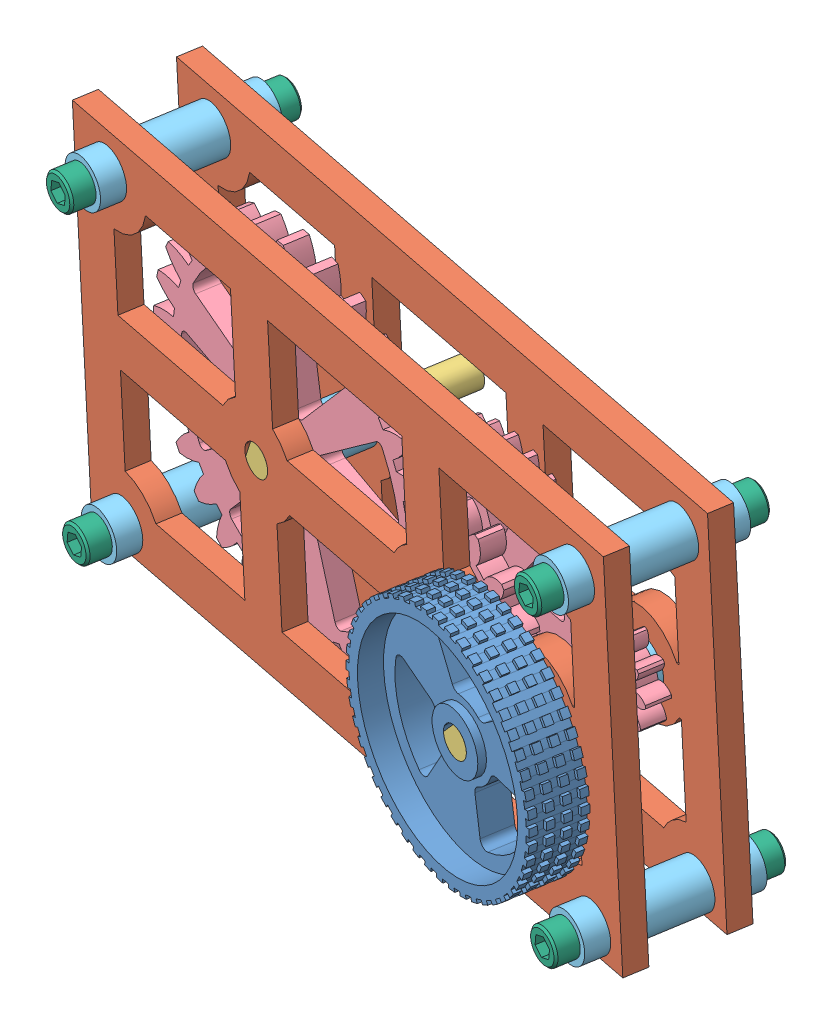
SolidWorks assembly gearbox, configuration Default. Lengths in mm.
Overall size (100.67 63.61 57.73).
40 component instances, 6 part files, 55 mates.
Components (placement in the parent):
- knob-1: knob [Default] at (7.9553 -111.4931 123.7361) x (-0.201949 -0.036611 0.978712) z (0.719883 -0.683113 0.122989) size (7 31.98 32.04)
- plate-1: plate [Default] at (-21.9045 -111.291 100.2126) x (-0.979202 -0.012363 -0.202512) z (0.201949 0.036611 -0.978712) size (93 50 3)
- sub 1-1: sub 1 [Default] at (23.1272 -130.4427 130.6283) x (-0.664068 -0.729395 -0.164309) z (0.201949 0.036611 -0.978712) size (13.97 13.6 25)
  - axle-1: axle [25 mm Tall] at (-2.6141 24.7144 -0.6247) size (4 3.5 25)
  - root_gear-1: root_gear [10T 1.0Mod] at (-2.6141 24.7144 17.3753) x (0.981831 0.18976 0) z (0 0 1) size (12 11.53 3)
  - spacer-3: spacer [1 mm Tall] at (-2.6141 24.7144 20.3753) size (6.2 6.2 1)
  - spacer-4: spacer [5 mm Tall] at (-2.6141 24.7144 12.3753) size (6.2 6.2 5)
- sub 2-1: sub 2 [Default] at (-36.8905 -107.9865 121.4817) x (0.835581 0.514845 0.191674) z (0.201949 0.036611 -0.978712) size (32 31.89 15)
  - root_gear-1: root_gear [30T 1.0Mod] at (18.8313 15.9897 19.7218) size (32 31.89 3)
  - root_gear-2: root_gear [10T 1.5Mod] at (18.8313 15.9897 15.7218) x (0.373168 0.927764 0) z (0 0 1) size (18 17.3 3)
  - axle-1: axle [15 mm Tall] at (18.8313 15.9897 11.7218) x (-0.639963 0.768406 0) z (0 0 1) size (4 3.5 15)
  - spacer-1: spacer [1 mm Tall] at (18.8313 15.9897 14.7218) size (6.2 6.2 1)
  - spacer-2: spacer [1 mm Tall] at (18.8313 15.9897 22.7218) size (6.2 6.2 1)
  - spacer-3: spacer [1 mm Tall] at (18.8313 15.9897 18.7218) size (6.2 6.2 1)
- sub 3-1: sub 3 [Default] at (-13.7078 -137.0358 71.116) x (0.370962 0.921986 0.111033) z (-0.201949 -0.036611 0.978712) size (48 47.84 25)
  - root_gear-1: root_gear [30T 1.5Mod] at (17.5723 27.0157 34.1899) size (48 47.84 3)
  - axle-1: axle [25 mm Tall] at (17.5723 27.0157 16.1899) size (4 3.5 25)
  - spacer-1: spacer [5 mm Tall] at (17.5723 27.0157 29.1899) size (6.2 6.2 5)
  - spacer-2: spacer [1 mm Tall] at (17.5723 27.0157 37.1899) size (6.2 6.2 1)
- plate-2: plate [Default] at (-24.3278 -111.7304 111.9571) x (-0.979202 -0.012363 -0.202512) z (0.201949 0.036611 -0.978712) size (93 50 3)
- spacer-10: spacer [2.85 mm ID] at (18.3421 -90.7929 109.2839) x (0.9729 0.107405 0.204767) z (-0.201949 -0.036611 0.978712) size (6.2 6.2 9)
- spacer-11: spacer [2.85 mm ID] at (-61.0956 -133.5261 91.2941) x (0.9729 0.107405 0.204767) z (-0.201949 -0.036611 0.978712) size (6.2 6.2 9)
- spacer-12: spacer [2.85 mm ID] at (-61.9104 -91.8061 92.6866) x (0.9729 0.107405 0.204767) z (-0.201949 -0.036611 0.978712) size (6.2 6.2 9)
- spacer-13: spacer [2.85 mm ID] at (19.1569 -132.5128 107.8914) x (0.9729 0.107405 0.204767) z (-0.201949 -0.036611 0.978712) size (6.2 6.2 9)
- spacer-14: spacer [3 mm ID] at (-64.3338 -92.2455 104.4311) x (0.979391 -0.010837 0.201684) z (-0.201949 -0.036611 0.978712) size (6.2 6.2 3)
- spacer-15: spacer [3 mm ID] at (19.5538 -90.5732 103.4116) x (0.979391 -0.010837 0.201684) z (-0.201949 -0.036611 0.978712) size (6.2 6.2 3)
- spacer-16: spacer [3 mm ID] at (20.3686 -132.2932 102.0191) x (0.979391 -0.010837 0.201684) z (-0.201949 -0.036611 0.978712) size (6.2 6.2 3)
- spacer-17: spacer [3 mm ID] at (-59.884 -133.3064 85.4218) x (0.979391 -0.010837 0.201684) z (-0.201949 -0.036611 0.978712) size (6.2 6.2 3)
- spacer-18: spacer [3 mm ID] at (-60.6987 -91.5865 86.8143) x (0.979391 -0.010837 0.201684) z (-0.201949 -0.036611 0.978712) size (6.2 6.2 3)
- spacer-19: spacer [3 mm ID] at (15.9187 -91.2322 121.0284) x (0.979391 -0.010837 0.201684) z (-0.201949 -0.036611 0.978712) size (6.2 6.2 3)
- spacer-20: spacer [3 mm ID] at (16.7335 -132.9522 119.6359) x (0.979391 -0.010837 0.201684) z (-0.201949 -0.036611 0.978712) size (6.2 6.2 3)
- spacer-21: spacer [3 mm ID] at (-63.519 -133.9654 103.0386) x (0.979391 -0.010837 0.201684) z (-0.201949 -0.036611 0.978712) size (6.2 6.2 3)
- socket head cap screw_ai-4: socket head cap screw_ai [HX-SHCS 0.112-40x0.375x0.375-N] at (14.7384 -91.4462 126.7488) x (0.201949 0.036611 -0.978712) z (0.968271 -0.157654 0.193897) size (12.37 4.65 4.65)
- socket head cap screw_ai-5: socket head cap screw_ai [HX-SHCS 0.112-40x0.375x0.375-N] at (20.1283 -90.4691 100.6274) x (-0.201949 -0.036611 0.978712) z (-0.95645 -0.20767 -0.205124) size (12.37 4.65 4.65)
- socket head cap screw_ai-6: socket head cap screw_ai [HX-SHCS 0.112-40x0.375x0.375-N] at (-60.1242 -91.4823 84.03) x (-0.201949 -0.036611 0.978712) z (-0.95645 -0.20767 -0.205124) size (12.37 4.65 4.65)
- socket head cap screw_ai-7: socket head cap screw_ai [HX-SHCS 0.112-40x0.375x0.375-N] at (-59.3095 -133.2023 82.6375) x (-0.201949 -0.036611 0.978712) z (-0.95645 -0.20767 -0.205124) size (12.37 4.65 4.65)
- socket head cap screw_ai-8: socket head cap screw_ai [HX-SHCS 0.112-40x0.375x0.375-N] at (20.9431 -132.189 99.2349) x (-0.201949 -0.036611 0.978712) z (-0.95645 -0.20767 -0.205124) size (12.37 4.65 4.65)
- socket head cap screw_ai-9: socket head cap screw_ai [HX-SHCS 0.112-40x0.375x0.375-N] at (-65.5141 -92.4595 110.1515) x (0.201949 0.036611 -0.978712) z (0.968271 -0.157654 0.193897) size (12.37 4.65 4.65)
- socket head cap screw_ai-10: socket head cap screw_ai [HX-SHCS 0.112-40x0.375x0.375-N] at (-64.6994 -134.1794 108.759) x (0.201949 0.036611 -0.978712) z (0.968271 -0.157654 0.193897) size (12.37 4.65 4.65)
- socket head cap screw_ai-11: socket head cap screw_ai [HX-SHCS 0.112-40x0.375x0.375-N] at (15.5531 -133.1661 125.3563) x (0.201949 0.036611 -0.978712) z (0.968271 -0.157654 0.193897) size (12.37 4.65 4.65)
Mates (geometry in assembly coordinates):
- Concentric10: concentric aligned: cylinder of plate-1 through (11.9942 -110.7608 104.1618) axis (-0.201949 -0.036611 0.978712) radius 2; cylinder of sub 1-1/axle-1 through (11.9942 -110.7608 104.1618) axis (-0.201949 -0.036611 0.978712) radius 2
- Concentric11: concentric aligned: cylinder of plate-1 through (-7.5898 -111.0081 100.1116) axis (-0.201949 -0.036611 0.978712) radius 2; cylinder of sub 2-1/axle-1 through (-7.5898 -111.0081 100.1116) axis (-0.201949 -0.036611 0.978712) radius 2
- Concentric12: concentric anti-aligned: cylinder of plate-1 through (-36.9658 -111.379 94.0362) axis (-0.201949 -0.036611 0.978712) radius 2; cylinder of sub 3-1/axle-1 through (-39.9951 -111.9282 108.7169) axis (0.201949 0.036611 -0.978712) radius 2
- Coincident3: coincident anti-aligned: plane of plate-1 through (-21.9045 -111.291 100.2126) normal (-0.201949 -0.036611 0.978712); plane of sub 3-1/spacer-1 through (-37.5717 -111.4888 96.9724) normal (0.201949 0.036611 -0.978712)
- Coincident4: coincident anti-aligned: plane of plate-1 through (-21.9045 -111.291 100.2126) normal (-0.201949 -0.036611 0.978712); plane of sub 2-1/spacer-2 through (-8.1956 -111.1179 103.0477) normal (0.201949 0.036611 -0.978712)
- Coincident5: coincident anti-aligned: plane of plate-1 through (-21.9045 -111.291 100.2126) normal (-0.201949 -0.036611 0.978712); plane of sub 1-1/spacer-3 through (11.3884 -110.8707 107.098) normal (0.201949 0.036611 -0.978712)
- Concentric24: concentric anti-aligned: cylinder of knob-1 through (7.9553 -111.4931 123.7361) axis (0.201949 0.036611 -0.978712) radius 2; cylinder of sub 1-1/axle-1 through (11.9942 -110.7608 104.1618) axis (-0.201949 -0.036611 0.978712) radius 2
- Coincident18: coincident aligned: plane of knob-1 through (4.066 -108.9437 128.1377) normal (-0.201949 -0.036611 0.978712); plane of sub 1-1/axle-1 through (6.9455 -111.6761 128.6296) normal (-0.201949 -0.036611 0.978712)
- Concentric34: concentric anti-aligned: cylinder of plate-2 through (16.5246 -91.1224 118.0923) axis (-0.201949 -0.036611 0.978712) radius 1.5; cylinder of spacer-10 through (16.5246 -91.1224 118.0923) axis (0.201949 0.036611 -0.978712) radius 1.425
- Coincident27: coincident anti-aligned: plane of plate-2 through (-23.722 -111.6205 109.021) normal (0.201949 0.036611 -0.978712); plane of spacer-10 through (16.5246 -91.1224 118.0923) normal (-0.201949 -0.036611 0.978712)
- Coincident28: coincident anti-aligned: plane of plate-1 through (-21.9045 -111.291 100.2126) normal (-0.201949 -0.036611 0.978712); plane of spacer-10 through (18.3421 -90.7929 109.2839) normal (0.201949 0.036611 -0.978712)
- Concentric35: concentric anti-aligned: cylinder of plate-1 through (18.948 -90.6831 106.3477) axis (-0.201949 -0.036611 0.978712) radius 1.5; cylinder of spacer-10 through (16.5246 -91.1224 118.0923) axis (0.201949 0.036611 -0.978712) radius 1.425
- Coincident29: coincident anti-aligned: plane of plate-1 through (-21.9045 -111.291 100.2126) normal (-0.201949 -0.036611 0.978712); plane of spacer-11 through (-61.0956 -133.5261 91.2941) normal (0.201949 0.036611 -0.978712)
- Coincident30: coincident anti-aligned: plane of plate-2 through (-23.722 -111.6205 109.021) normal (0.201949 0.036611 -0.978712); plane of spacer-11 through (-62.9132 -133.8556 100.1025) normal (-0.201949 -0.036611 0.978712)
- Concentric36: concentric anti-aligned: cylinder of plate-1 through (-60.4898 -133.4162 88.3579) axis (-0.201949 -0.036611 0.978712) radius 1.5; cylinder of spacer-11 through (-62.9132 -133.8556 100.1025) axis (0.201949 0.036611 -0.978712) radius 1.425
- Concentric37: concentric anti-aligned: cylinder of plate-2 through (-62.9132 -133.8556 100.1025) axis (-0.201949 -0.036611 0.978712) radius 1.5; cylinder of spacer-11 through (-62.9132 -133.8556 100.1025) axis (0.201949 0.036611 -0.978712) radius 1.425
- Concentric38: concentric anti-aligned: cylinder of plate-1 through (-61.3045 -91.6963 89.7504) axis (-0.201949 -0.036611 0.978712) radius 1.5; cylinder of spacer-12 through (-63.7279 -92.1356 101.495) axis (0.201949 0.036611 -0.978712) radius 1.425
- Concentric39: concentric anti-aligned: cylinder of plate-1 through (19.7627 -132.403 104.9552) axis (-0.201949 -0.036611 0.978712) radius 1.5; cylinder of spacer-13 through (17.3393 -132.8423 116.6998) axis (0.201949 0.036611 -0.978712) radius 1.425
- Coincident31: coincident anti-aligned: plane of plate-1 through (-21.9045 -111.291 100.2126) normal (-0.201949 -0.036611 0.978712); plane of spacer-12 through (-61.9104 -91.8061 92.6866) normal (0.201949 0.036611 -0.978712)
- Coincident32: coincident anti-aligned: plane of plate-1 through (-21.9045 -111.291 100.2126) normal (-0.201949 -0.036611 0.978712); plane of spacer-13 through (19.1569 -132.5128 107.8914) normal (0.201949 0.036611 -0.978712)
- Coincident33: coincident anti-aligned: plane of plate-1 through (-21.2986 -111.1812 97.2764) normal (0.201949 0.036611 -0.978712); plane of spacer-15 through (18.948 -90.6831 106.3477) normal (-0.201949 -0.036611 0.978712)
- Coincident34: coincident anti-aligned: plane of plate-1 through (-21.2986 -111.1812 97.2764) normal (0.201949 0.036611 -0.978712); plane of spacer-18 through (-61.3045 -91.6963 89.7504) normal (-0.201949 -0.036611 0.978712)
- Coincident35: coincident anti-aligned: plane of plate-1 through (-21.2986 -111.1812 97.2764) normal (0.201949 0.036611 -0.978712); plane of spacer-17 through (-60.4898 -133.4162 88.3579) normal (-0.201949 -0.036611 0.978712)
- Coincident36: coincident anti-aligned: plane of plate-1 through (-21.2986 -111.1812 97.2764) normal (0.201949 0.036611 -0.978712); plane of spacer-16 through (19.7627 -132.403 104.9552) normal (-0.201949 -0.036611 0.978712)
- Coincident37: coincident anti-aligned: plane of plate-2 through (-24.3278 -111.7304 111.9571) normal (-0.201949 -0.036611 0.978712); plane of spacer-20 through (16.7335 -132.9522 119.6359) normal (0.201949 0.036611 -0.978712)
- Coincident38: coincident anti-aligned: plane of plate-2 through (-24.3278 -111.7304 111.9571) normal (-0.201949 -0.036611 0.978712); plane of spacer-19 through (15.9187 -91.2322 121.0284) normal (0.201949 0.036611 -0.978712)
- Coincident39: coincident anti-aligned: plane of plate-2 through (-24.3278 -111.7304 111.9571) normal (-0.201949 -0.036611 0.978712); plane of spacer-21 through (-63.519 -133.9654 103.0386) normal (0.201949 0.036611 -0.978712)
- Coincident40: coincident anti-aligned: plane of plate-2 through (-24.3278 -111.7304 111.9571) normal (-0.201949 -0.036611 0.978712); plane of spacer-14 through (-64.3338 -92.2455 104.4311) normal (0.201949 0.036611 -0.978712)
- Concentric40: concentric anti-aligned: cylinder of plate-2 through (16.5246 -91.1224 118.0923) axis (-0.201949 -0.036611 0.978712) radius 1.5; cylinder of spacer-19 through (15.3129 -91.342 123.9645) axis (0.201949 0.036611 -0.978712) radius 1.5
- Concentric41: concentric anti-aligned: cylinder of plate-2 through (-63.7279 -92.1356 101.495) axis (-0.201949 -0.036611 0.978712) radius 1.5; cylinder of spacer-14 through (-64.9396 -92.3553 107.3672) axis (0.201949 0.036611 -0.978712) radius 1.5
- Concentric42: concentric anti-aligned: cylinder of plate-2 through (-62.9132 -133.8556 100.1025) axis (-0.201949 -0.036611 0.978712) radius 1.5; cylinder of spacer-21 through (-64.1249 -134.0752 105.9747) axis (0.201949 0.036611 -0.978712) radius 1.5
- Concentric43: concentric anti-aligned: cylinder of plate-2 through (17.3393 -132.8423 116.6998) axis (-0.201949 -0.036611 0.978712) radius 1.5; cylinder of spacer-20 through (16.1276 -133.062 122.572) axis (0.201949 0.036611 -0.978712) radius 1.5
- Concentric44: concentric anti-aligned: cylinder of plate-1 through (19.7627 -132.403 104.9552) axis (-0.201949 -0.036611 0.978712) radius 1.5; cylinder of spacer-16 through (19.7627 -132.403 104.9552) axis (0.201949 0.036611 -0.978712) radius 1.5
- Concentric45: concentric anti-aligned: cylinder of plate-1 through (18.948 -90.6831 106.3477) axis (-0.201949 -0.036611 0.978712) radius 1.5; cylinder of spacer-15 through (18.948 -90.6831 106.3477) axis (0.201949 0.036611 -0.978712) radius 1.5
- Concentric47: concentric anti-aligned: cylinder of plate-1 through (-61.3045 -91.6963 89.7504) axis (-0.201949 -0.036611 0.978712) radius 1.5; cylinder of spacer-18 through (-61.3045 -91.6963 89.7504) axis (0.201949 0.036611 -0.978712) radius 1.5
- Concentric48: concentric anti-aligned: cylinder of plate-1 through (-60.4898 -133.4162 88.3579) axis (-0.201949 -0.036611 0.978712) radius 1.5; cylinder of spacer-17 through (-60.4898 -133.4162 88.3579) axis (0.201949 0.036611 -0.978712) radius 1.5
- Concentric49: concentric anti-aligned: cylinder of spacer-19 through (15.3129 -91.342 123.9645) axis (0.201949 0.036611 -0.978712) radius 1.5; cylinder of socket head cap screw_ai-4 through (8.3265 -92.6086 157.8229) axis (-0.201949 -0.036611 0.978712) radius 2.3241
- Coincident41: coincident anti-aligned: plane of spacer-19 through (15.3129 -91.342 123.9645) normal (-0.201949 -0.036611 0.978712); plane of socket head cap screw_ai-4 through (15.655 -89.0486 124.1209) normal (0.201949 0.036611 -0.978712)
- Concentric50: concentric aligned: cylinder of spacer-15 through (18.948 -90.6831 106.3477) axis (0.201949 0.036611 -0.978712) radius 1.5; cylinder of socket head cap screw_ai-5 through (26.5402 -89.3067 69.5533) axis (0.201949 0.036611 -0.978712) radius 2.3241
- Coincident42: coincident anti-aligned: plane of spacer-15 through (19.5538 -90.5732 103.4116) normal (0.201949 0.036611 -0.978712); plane of socket head cap screw_ai-5 through (19.064 -88.3014 103.3955) normal (-0.201949 -0.036611 0.978712)
- Concentric51: concentric aligned: cylinder of spacer-18 through (-61.3045 -91.6963 89.7504) axis (0.201949 0.036611 -0.978712) radius 1.5; cylinder of socket head cap screw_ai-6 through (-53.7123 -90.3199 52.9559) axis (0.201949 0.036611 -0.978712) radius 2.3241
- Coincident43: coincident anti-aligned: plane of spacer-18 through (-60.6987 -91.5865 86.8143) normal (0.201949 0.036611 -0.978712); plane of socket head cap screw_ai-6 through (-61.1885 -89.3146 86.7982) normal (-0.201949 -0.036611 0.978712)
- Concentric52: concentric aligned: cylinder of spacer-17 through (-60.4898 -133.4162 88.3579) axis (0.201949 0.036611 -0.978712) radius 1.5; cylinder of socket head cap screw_ai-7 through (-52.8976 -132.0399 51.5635) axis (0.201949 0.036611 -0.978712) radius 2.3241
- Coincident44: coincident anti-aligned: plane of spacer-17 through (-59.884 -133.3064 85.4218) normal (0.201949 0.036611 -0.978712); plane of socket head cap screw_ai-7 through (-60.3738 -131.0346 85.4057) normal (-0.201949 -0.036611 0.978712)
- Concentric53: concentric aligned: cylinder of spacer-16 through (19.7627 -132.403 104.9552) axis (0.201949 0.036611 -0.978712) radius 1.5; cylinder of socket head cap screw_ai-8 through (27.3549 -131.0266 68.1608) axis (0.201949 0.036611 -0.978712) radius 2.3241
- Coincident45: coincident anti-aligned: plane of spacer-16 through (20.3686 -132.2932 102.0191) normal (0.201949 0.036611 -0.978712); plane of socket head cap screw_ai-8 through (19.8787 -130.0213 102.003) normal (-0.201949 -0.036611 0.978712)
- Concentric54: concentric anti-aligned: cylinder of spacer-14 through (-64.9396 -92.3553 107.3672) axis (0.201949 0.036611 -0.978712) radius 1.5; cylinder of socket head cap screw_ai-9 through (-71.926 -93.6218 141.2256) axis (-0.201949 -0.036611 0.978712) radius 2.3241
- Coincident46: coincident anti-aligned: plane of spacer-14 through (-64.9396 -92.3553 107.3672) normal (-0.201949 -0.036611 0.978712); plane of socket head cap screw_ai-9 through (-64.5975 -90.0618 107.5236) normal (0.201949 0.036611 -0.978712)
- Concentric55: concentric anti-aligned: cylinder of spacer-21 through (-64.1249 -134.0752 105.9747) axis (0.201949 0.036611 -0.978712) radius 1.5; cylinder of socket head cap screw_ai-10 through (-71.1113 -135.3418 139.8331) axis (-0.201949 -0.036611 0.978712) radius 2.3241
- Coincident47: coincident anti-aligned: plane of spacer-21 through (-64.1249 -134.0752 105.9747) normal (-0.201949 -0.036611 0.978712); plane of socket head cap screw_ai-10 through (-63.7828 -131.7818 106.1311) normal (0.201949 0.036611 -0.978712)
- Concentric56: concentric anti-aligned: cylinder of spacer-20 through (16.1276 -133.062 122.572) axis (0.201949 0.036611 -0.978712) radius 1.5; cylinder of socket head cap screw_ai-11 through (9.1413 -134.3285 156.4304) axis (-0.201949 -0.036611 0.978712) radius 2.3241
- Coincident48: coincident anti-aligned: plane of spacer-20 through (16.1276 -133.062 122.572) normal (-0.201949 -0.036611 0.978712); plane of socket head cap screw_ai-11 through (16.4697 -130.7685 122.7284) normal (0.201949 0.036611 -0.978712)
- GearMate2: gear = 48 : 16 mm: circle of sub 2-1/root_gear-2; circle of sub 3-1/root_gear-1
- GearMate3: gear = 1 : 3 mm: circle of sub 2-1/root_gear-1; circle of sub 1-1/root_gear-1
- Parallel1: parallel anti-aligned: plane of knob-1 through (7.9553 -111.4931 123.7361) normal (0.719883 -0.683113 0.122989); plane of sub 1-1/axle-1 through (11.7929 -108.7713 104.1947) normal (-0.719883 0.683113 -0.122989)
